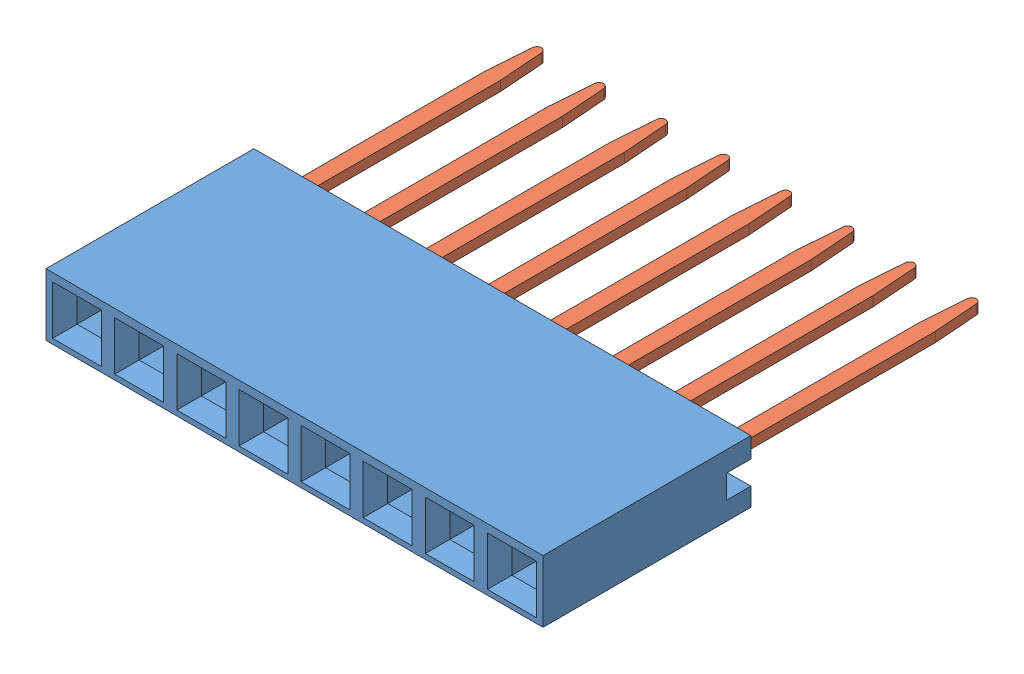
SolidWorks assembly 960240-6202-AR 1x8 long, configuration Default. Lengths in mm.
Overall size (20.32 2.54 18.99).
9 component instances, 2 part files, 4 mates.
Components (placement in the parent):
- 960240-6202-AR Body8-1: 960240-6202-AR Body8 [Default] at (10.16 -1.27 8.5) size (20.32 2.54 8.5)
- 960240-6202-AR Pin Long-1: 960240-6202-AR Pin Long [Default] at (8.89 0.04 -0.7572) x (1 0 0) z (0 -1 0) size (2 16.99 0.4)
- 960240-6202-AR Pin Long-3: 960240-6202-AR Pin Long [Default] at (6.35 0.04 -0.7572) x (1 0 0) z (0 -1 0) size (2 16.99 0.4)
- 960240-6202-AR Pin Long-5: 960240-6202-AR Pin Long [Default] at (3.81 0.04 -0.7572) x (1 0 0) z (0 -1 0) size (2 16.99 0.4)
- 960240-6202-AR Pin Long-7: 960240-6202-AR Pin Long [Default] at (1.27 0.04 -0.7572) x (1 0 0) z (0 -1 0) size (2 16.99 0.4)
- 960240-6202-AR Pin Long-9: 960240-6202-AR Pin Long [Default] at (-1.27 0.04 -0.7572) x (1 0 0) z (0 -1 0) size (2 16.99 0.4)
- 960240-6202-AR Pin Long-11: 960240-6202-AR Pin Long [Default] at (-3.81 0.04 -0.7572) x (1 0 0) z (0 -1 0) size (2 16.99 0.4)
- 960240-6202-AR Pin Long-13: 960240-6202-AR Pin Long [Default] at (-6.35 0.04 -0.7572) x (1 0 0) z (0 -1 0) size (2 16.99 0.4)
- 960240-6202-AR Pin Long-15: 960240-6202-AR Pin Long [Default] at (-8.89 0.04 -0.7572) x (1 0 0) z (0 -1 0) size (2 16.99 0.4)
Mates (geometry in assembly coordinates):
- Coincident1: coincident anti-aligned: plane of 960240-6202-AR Pin Long-1 through (8.9056 -0.16 -10.2904) normal (0 -1 0); plane of 960240-6202-AR Body8-1 through (7.89 -0.16 6.5) normal (0 1 0)
- Tangent1: tangent anti-aligned: plane of 960240-6202-AR Body8-1 through (10.16 -1.27 6.5) normal (0 0 -1); cylinder of 960240-6202-AR Pin Long-1 through (9.69 0.24 6.3) axis (0 -1 0) radius 0.2
- Coincident2: coincident anti-aligned: plane of 960240-6202-AR Body8-1 through (9.89 -0.16 6.5) normal (-1 0 0); plane of 960240-6202-AR Pin Long-1 through (9.89 0.24 0.9096) normal (1 0 0)
- Coincident5: coordinate: point of 960240-6202-AR Body8-1
